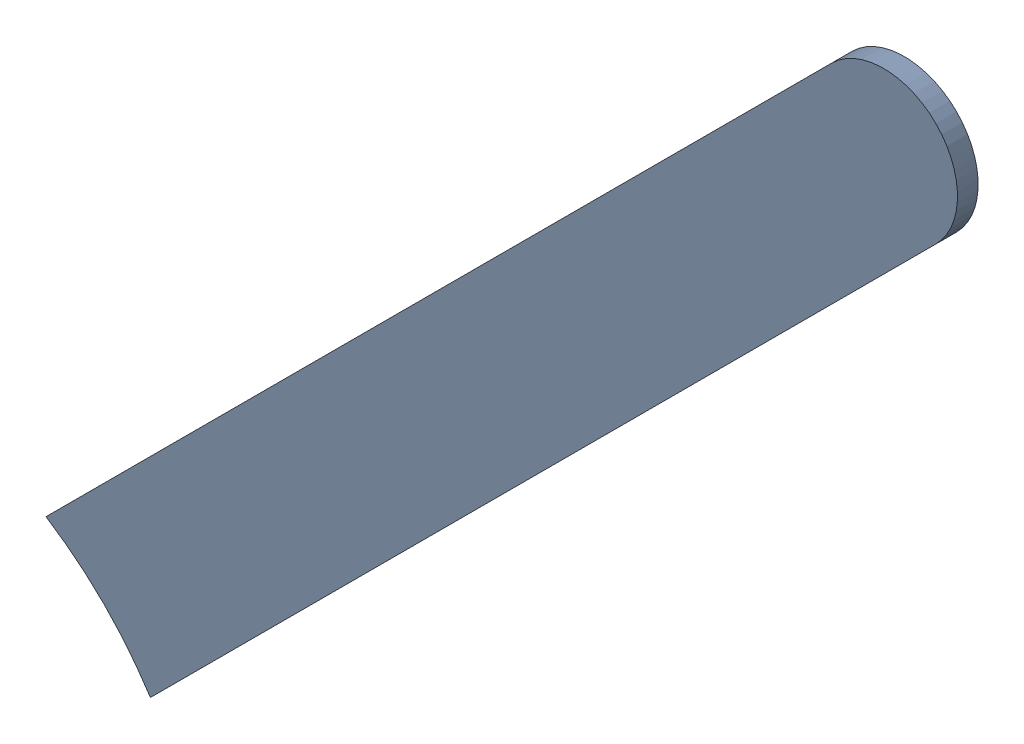
SolidWorks assembly Track (13.758mm,59.438mm)(15.521mm,61.2mm) on Bottom Layer, configuration Predeterminado. Lengths in mm.
Overall size (1.57 1.57 0.04).
2 component instances, 1 part files, 0 mates.
Components (placement in the parent):
- Track (13.758mm,59.438mm)(15.521mm,61.2mm) on Bottom Layer-1-1: Track (13.758mm,59.438mm)(15.521mm,61.2mm) on Bottom Layer-1 [Predeterminado] at (-68.317 -44.187 -0.4013) size (1.57 1.57 0.04)
  - Track (13.758mm,59.438mm)(15.521mm,61.2mm) on Bottom Layer-Part-1-1: Track (13.758mm,59.438mm)(15.521mm,61.2mm) on Bottom Layer-Part-1 [Predeterminado] at origin size (1.57 1.57 0.04)
